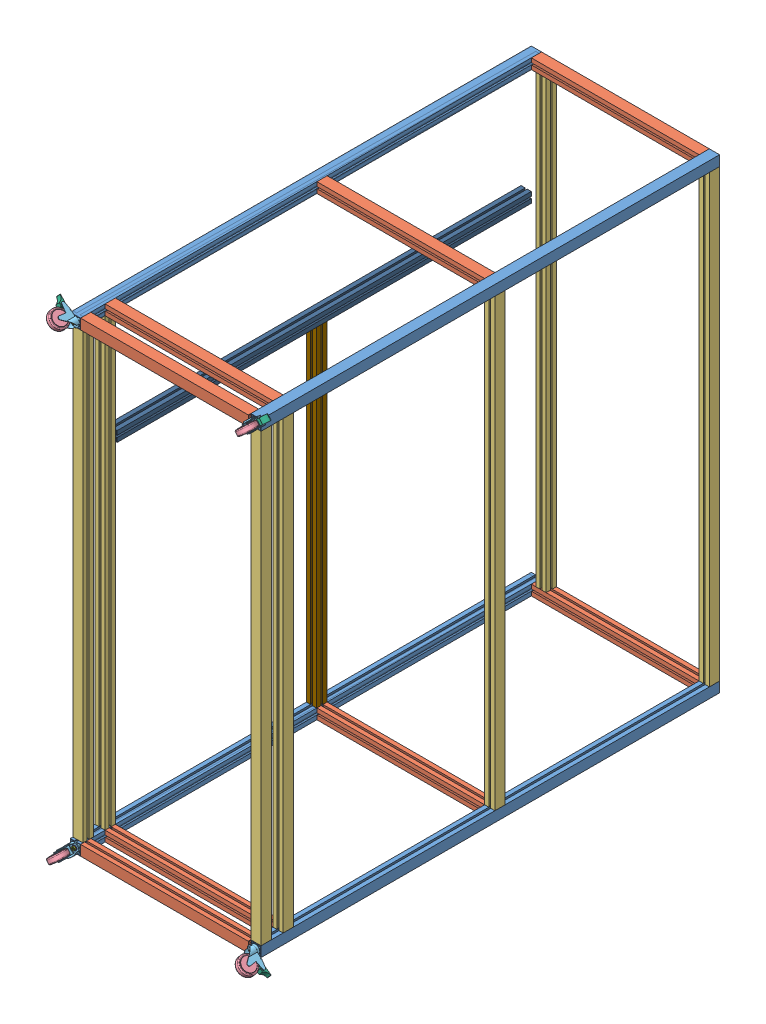
SolidWorks assembly big_cage_north, configuration Default. Lengths in mm.
Overall size (956.09 2161.48 2112.95).
48 component instances, 10 part files, 13 mates.
Components (placement in the parent):
- 20.1028 45X45 G_79_25in-1: 20.1028 45X45 G_79_25in [Default] at (-423.3035 1420.7972 820.7716) size (45 45 2012.95)
- 20.1028 45X45 G_29in-1: 20.1028 45X45 G_29in [Default] at (-400.8029 1420.7972 2811.2221) x (0 0 -1) z (1 0 0) size (45 45 736.6)
- 20.1028 45X45 G_29in-2: 20.1028 45X45 G_29in [Default] at (335.7971 1420.7972 832.3491) x (0 0 1) z (-1 0 0) size (45 45 736.6)
- 20.1028 45X45 G_29in-3: 20.1028 45X45 G_29in [inner] at (335.7971 1420.797 1773.7803) x (0 -1 0) z (-1 0 0) size (45 45 736.6)
- 20.1028 45X45 G_79_25in-2: 20.1028 45X45 G_79_25in [Default] at (358.2976 1420.7972 2822.7996) x (-1 0 0) z (0 0 -1) size (45 45 2012.95)
- 20.1028 45X45 G_76in-1: 20.1028 45X45 G_76in [Default] at (358.2977 -557.5035 832.3491) x (0 0 1) z (0 1 0) size (45 45 1955.8)
- 20.1028 45X45 G_76in-3: 20.1028 45X45 G_76in [inner] at (358.2976 1398.2965 1773.7789) x (-1 0 0) z (0 -1 0) size (45 45 1955.8)
- 20.1028 45X45 G_29in-4: 20.1028 45X45 G_29in [Default] at (-400.803 -580.0042 832.3491) x (0 0 1) z (1 0 0) size (45 45 736.6)
- 20.1028 45X45 G_79_25in-3: 20.1028 45X45 G_79_25in [Default] at (-423.3035 -580.0042 2833.7216) x (1 0 0) z (0 0 -1) size (45 45 2012.95)
- 20.1028 45X45 G_79_25in-4: 20.1028 45X45 G_79_25in [Default] at (358.2975 -580.0042 809.8496) x (-1 0 0) z (0 0 1) size (45 45 2012.95)
- 20.1028 45X45 G_29in-5: 20.1028 45X45 G_29in [Default] at (335.797 -580.0042 2811.2221) x (0 0 -1) z (-1 0 0) size (45 45 736.6)
- 20.1028 45X45 G_29in-6: 20.1028 45X45 G_29in [inner] at (-400.803 -580.004 1773.7803) x (0 1 0) z (1 0 0) size (45 45 736.6)
- 20.1028 45X45 G_79_25in-5: 20.1028 45X45 G_79_25in [Default] at (-423.3035 1420.7972 809.8496) size (45 45 2012.95)
- 20.1028 45X45 G_76in-4: 20.1028 45X45 G_76in [Default] at (358.2977 -557.5035 832.3491) x (0 0 1) z (0 1 0) size (45 45 1955.8)
- 20.1028 45X45 G_79_25in-6: 20.1028 45X45 G_79_25in [Default] at (-423.3035 -580.0042 2822.7996) x (1 0 0) z (0 0 -1) size (45 45 2012.95)
- 20.1028 45X45 G_76in-6: 20.1028 45X45 G_76in [Default] at (358.2978 1398.2965 2800.3001) x (0 0 -1) z (0 -1 0) size (45 45 1955.8)
- 20.1028 45X45 G_76in-7: 20.1028 45X45 G_76in [inner] at (358.2975 -557.5035 2703.4203) x (-1 0 0) z (0 1 0) size (45 45 1955.8)
- 20.1028 45X45 G_29in-7: 20.1028 45X45 G_29in [inner] at (335.797 -580.004 2703.4189) x (0 1 0) z (-1 0 0) size (45 45 736.6)
- 20.1028 45X45 G_29in-8: 20.1028 45X45 G_29in [inner] at (-400.8029 1420.797 2703.4189) x (0 -1 0) z (1 0 0) size (45 45 736.6)
- 20.1028 45X45 G_76in-8: 20.1028 45X45 G_76in [inner] at (-423.3035 1398.2965 2703.4203) x (1 0 0) z (0 -1 0) size (45 45 1955.8)
- 20.1028 45X45 G_76in-9: 20.1028 45X45 G_76in [Default] at (-423.3037 -557.5035 2800.3001) x (0 0 -1) z (0 1 0) size (45 45 1955.8)
- 21.1120 WHEEL WITH BRAKE-1: 21.1120 WHEEL WITH BRAKE [Default] at (381.943 -600.815 2885.2996) x (0.750665 -0.660683 0) z (0 0 -1) size (118.74 42 113.5)
  - 21.1120 WHEEL 75mm-1: 21.1120 WHEEL 75mm [Default] at origin size (75 23.5 75)
  - 21.1120 FORK-1: 21.1120 FORK [Default] at (-31.5 0 62.5) size (92.98 42 72)
  - 21.1120 BRAKE-1: 21.1120 BRAKE [Default] at (-28.5589 0 56.3657) x (0.995113 0 0.098744) z (-0.098744 0 0.995113) size (45.98 24 19)
  - SHCS M10X30 LOW HEAD DIN 7984-1: SHCS M10X30 LOW HEAD DIN 7984 [Default] at (-31.5 0 46) x (0 0 1) z (-1 0 0) size (36 16 16)
  - WAHSER M10 ROUND DIN 125-1A FOR WHEEL-1: WAHSER M10 ROUND DIN 125-1A FOR WHEEL [Default] at (-31.5 0 46) x (0 0 1) z (-1 0 0) size (2 20 20)
- 21.1120 WHEEL WITH BRAKE-2: 21.1120 WHEEL WITH BRAKE [Default] at (381.943 1441.608 2885.2996) x (0.750665 0.660683 0) z (0 0 -1) size (118.74 42 113.5)
  - 21.1120 WHEEL 75mm-1: 21.1120 WHEEL 75mm [Default] at origin size (75 23.5 75)
  - 21.1120 FORK-1: 21.1120 FORK [Default] at (-31.5 0 62.5) size (92.98 42 72)
  - 21.1120 BRAKE-1: 21.1120 BRAKE [Default] at (-28.5589 0 56.3657) x (0.995113 0 0.098744) z (-0.098744 0 0.995113) size (45.98 24 19)
  - SHCS M10X30 LOW HEAD DIN 7984-1: SHCS M10X30 LOW HEAD DIN 7984 [Default] at (-31.5 0 46) x (0 0 1) z (-1 0 0) size (36 16 16)
  - WAHSER M10 ROUND DIN 125-1A FOR WHEEL-1: WAHSER M10 ROUND DIN 125-1A FOR WHEEL [Default] at (-31.5 0 46) x (0 0 1) z (-1 0 0) size (2 20 20)
- 21.1120 WHEEL WITH BRAKE-3: 21.1120 WHEEL WITH BRAKE [Default] at (-446.9489 -600.815 2885.2996) x (-0.750665 -0.660683 0) z (0 0 -1) size (118.74 42 113.5)
  - 21.1120 WHEEL 75mm-1: 21.1120 WHEEL 75mm [Default] at origin size (75 23.5 75)
  - 21.1120 FORK-1: 21.1120 FORK [Default] at (-31.5 0 62.5) size (92.98 42 72)
  - 21.1120 BRAKE-1: 21.1120 BRAKE [Default] at (-28.5589 0 56.3657) x (0.995113 0 0.098744) z (-0.098744 0 0.995113) size (45.98 24 19)
  - SHCS M10X30 LOW HEAD DIN 7984-1: SHCS M10X30 LOW HEAD DIN 7984 [Default] at (-31.5 0 46) x (0 0 1) z (-1 0 0) size (36 16 16)
  - WAHSER M10 ROUND DIN 125-1A FOR WHEEL-1: WAHSER M10 ROUND DIN 125-1A FOR WHEEL [Default] at (-31.5 0 46) x (0 0 1) z (-1 0 0) size (2 20 20)
- 21.1120 WHEEL WITH BRAKE-4: 21.1120 WHEEL WITH BRAKE [Default] at (-446.9489 1441.608 2885.2996) x (-0.750665 0.660683 0) z (0 0 -1) size (118.74 42 113.5)
  - 21.1120 WHEEL 75mm-1: 21.1120 WHEEL 75mm [Default] at origin size (75 23.5 75)
  - 21.1120 FORK-1: 21.1120 FORK [Default] at (-31.5 0 62.5) size (92.98 42 72)
  - 21.1120 BRAKE-1: 21.1120 BRAKE [Default] at (-28.5589 0 56.3657) x (0.995113 0 0.098744) z (-0.098744 0 0.995113) size (45.98 24 19)
  - SHCS M10X30 LOW HEAD DIN 7984-1: SHCS M10X30 LOW HEAD DIN 7984 [Default] at (-31.5 0 46) x (0 0 1) z (-1 0 0) size (36 16 16)
  - WAHSER M10 ROUND DIN 125-1A FOR WHEEL-1: WAHSER M10 ROUND DIN 125-1A FOR WHEEL [Default] at (-31.5 0 46) x (0 0 1) z (-1 0 0) size (2 20 20)
- 20.1028 45X45 G_57in-2: 20.1028 45X45 G_57in [inner] at (-423.3035 890.2965 1774.7963) x (1 0 0) z (0 -1 0) size (45 45 1447.8)
- 20.1028 45X45 G_71_57in-1: 20.1028 45X45 G_71_57in [inner] at (-423.3035 912.7972 854.8496) size (45 45 1817.88)
- 20.1028 45X45 G_76in-10: 20.1028 45X45 G_76in [Default] at (-358.2978 1398.2965 832.3491) x (0 0 1) z (0 -1 0) size (45 45 1955.8)
Mates (geometry in assembly coordinates):
- Coincident1: coincident anti-aligned: plane of 20.1028 45X45 G_79_25in-1 through (-400.8029 1420.7972 2833.7216) normal (1 0 0); plane of 20.1028 45X45 G_29in-1 through (-400.8029 1420.7972 2811.2221) normal (-1 0 0)
- Coincident2: coincident anti-aligned: line of 20.1028 45X45 G_79_25in-1 through (-400.8029 1398.2965 2833.7216) axis (0 1 0); line of 20.1028 45X45 G_29in-1 through (-400.8029 1443.2965 2833.7216) axis (0 -1 0)
- Coincident3: coincident anti-aligned: line of 20.1028 45X45 G_79_25in-1 through (-400.8029 1443.2965 2833.7216) axis (0 0 -1); line of 20.1028 45X45 G_29in-1 through (-400.8029 1443.2965 2788.7216) axis (0 0 1)
- Coincident11: coincident aligned: line of 20.1028 45X45 G_79_25in-1 through (-400.8029 1443.2965 2833.7216) axis (0 0 -1); line of 20.1028 45X45 G_29in-3 through (-400.8029 1443.2965 1796.2796) axis (0 0 -1)
- Coincident12: coincident: point of 20.1028 45X45 G_29in-3
- Coincident13: coincident anti-aligned: plane of 20.1028 45X45 G_79_25in-1 through (-400.8029 1420.7972 2833.7216) normal (1 0 0); plane of 20.1028 45X45 G_29in-3 through (-400.8029 1420.797 1773.7803) normal (-1 0 0)
- Coincident14: coincident anti-aligned: plane of 20.1028 45X45 G_79_25in-2 through (358.2976 1398.2965 809.8496) normal (0 -1 0); plane of 20.1028 45X45 G_76in-1 through (358.2978 1398.2965 832.3491) normal (0 1 0)
- Coincident15: coincident anti-aligned: line of 20.1028 45X45 G_79_25in-2 through (380.7971 1398.2965 809.8496) axis (0 0 1); line of 20.1028 45X45 G_76in-1 through (380.7971 1398.2965 854.8496) axis (0 0 -1)
- Coincident16: coincident aligned: line of 20.1028 45X45 G_79_25in-2 through (380.7971 1398.2965 809.8496) axis (-1 0 0); line of 20.1028 45X45 G_76in-1 through (380.7971 1398.2965 809.8496) axis (-1 0 0)
- Coincident20: coincident: plane of 20.1028 45X45 G_29in-3 through (-400.8029 1420.797 1751.2796) normal (0 0 -1); plane of 20.1028 45X45 G_76in-3 through (358.2975 -557.5035 1751.2796) normal (0 0 -1)
- Coincident32: coincident: line of 20.1028 45X45 G_79_25in-3 through (-445.803 -557.5035 820.7716) axis (0 0 1); line of 20.1028 45X45 G_57in-2 through (-445.803 -557.5035 1797.2956) axis (0 0 -1)
- Coincident33: coincident aligned: line of 20.1028 45X45 G_57in-2 through (-445.803 890.2965 1797.2956) axis (0 0 -1); line of 20.1028 45X45 G_71_5in-1 through (-445.803 890.2965 2672.7276) axis (0 0 -1)
- Coincident37: coincident anti-aligned: plane of 20.1028 45X45 G_76in-4 through (358.2978 1398.2965 854.8496) normal (0 0 1); plane of 20.1028 45X45 G_71_5in-1 through (-423.3035 912.7972 854.8496) normal (0 0 -1)
